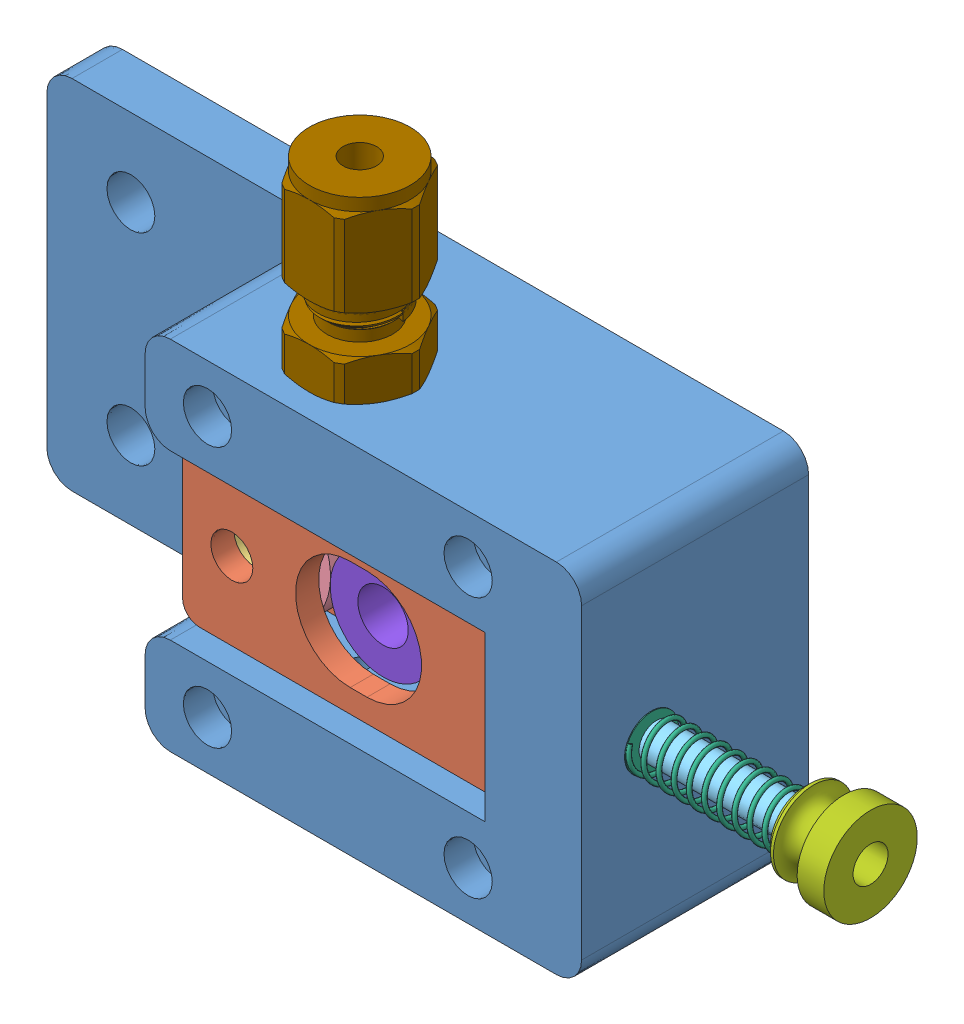
SolidWorks assembly FF-ASSY, configuration Default. Lengths in mm.
Overall size (110.17 63.8 27).
11 component instances, 10 part files, 22 mates.
Components (placement in the parent):
- P-FF-003_REV_1-1: P-FF-003_REV_1 [Default] at (4.8494 9.0702 -18.7155) size (84.61 42.5 27)
- P-FF-002_REV_1-1: P-FF-002_REV_1 [Default] at (-242.3493 -219.6941 -6.7755) size (36.5 24.5 12.5)
- washer-1: washer [Default] at (-2.4333 8.1219 2.9745) x (0.619734 -0.784812 0) z (0.784812 0.619734 0) size (8 1 8)
- washer-2: washer [Default] at (-2.4333 8.1219 -3.0255) x (-0.055167 -0.998477 0) z (0.998477 -0.055167 0) size (8 1 8)
- pusher bearing-1: pusher bearing [Default] at (-63.7572 32.1432 47.0234) x (0 0 -1) z (-0.364729 -0.931114 0) size (5 15.97 15.97)
- bolt-1: bolt [Default] at (24.2063 -23.1566 -17.7934) x (-1 0 0) z (0 0.99375 -0.111626) size (41.1 6.67 7.23)
- spring-1: spring [Default] at (41.8324 8.2291 0.0161) x (0 -0.407555 -0.913181) z (-1 0 0) size (6.79 7.12 18.5)
- knob-1: knob [Default] at (41.8278 -2.2663 4.1827) x (1 0 0) z (0 0.412808 0.910818) size (7.79 11.11 11.11)
- pusher motor-1: pusher motor [Default] at (12.7324 8.1219 -18.7155)
- pusher gear-1: pusher gear [Default] at (1.1826 -36.9282 46.7292) x (0 0 -1) z (0.968672 -0.248344 0) size (10.97 12.57 12.57)
- fitting-1: fitting [5305K261] at (6.5324 38.7719 -0.5255) x (0.866025 0 0.5) z (0 1 0) size (12 13.36 21.32)
Mates (geometry in assembly coordinates):
- Concentric1: concentric aligned: cylinder of P-FF-003_REV_1-1 through (41.7324 8.1219 -0.5255) axis (-1 0 0) radius 2.25; cylinder of P-FF-002_REV_1-1 through (28.2063 8.1219 -0.5255) axis (-1 0 0) radius 2.5
- Parallel1: parallel aligned: plane of P-FF-003_REV_1-1 through (38.7324 26.3719 8.2845) normal (0 0 1); plane of P-FF-002_REV_1-1 through (28.2063 -1.1281 5.7245) normal (0 0 1)
- Coincident1: coincident anti-aligned: plane of P-FF-002_REV_1-1 through (-8.2937 -1.1281 2.9745) normal (0 0 -1); plane of washer-1 through (-2.4333 8.1219 2.9745) normal (0 0 1)
- Concentric2: concentric aligned: cylinder of P-FF-002_REV_1-1 through (-2.4333 8.1219 2.9745) axis (0 0 1) radius 2.5; cylinder of washer-1 through (-2.4333 8.1219 1.9745) axis (0 0 1) radius 2.5
- Coincident2: coincident anti-aligned: plane of P-FF-002_REV_1-1 through (-8.2937 -1.1281 -4.0255) normal (0 0 1); plane of washer-2 through (-2.4333 8.1219 -4.0255) normal (0 0 -1)
- Concentric3: concentric anti-aligned: cylinder of P-FF-002_REV_1-1 through (-2.4333 8.1219 5.7245) axis (0 0 -1) radius 3.45; cylinder of washer-2 through (-2.4333 8.1219 -4.0255) axis (0 0 1) radius 2.5
- Coincident3: coincident anti-aligned: plane of washer-2 through (-2.4333 8.1219 -3.0255) normal (0 0 1); plane of pusher bearing-1 through (-3.0589 8.3669 -3.0255) normal (0 0 -1)
- Concentric4: concentric aligned: cylinder of washer-2 through (-2.4333 8.1219 -4.0255) axis (0 0 1) radius 2.5; cylinder of pusher bearing-1 through (-2.4333 8.1219 1.9745) axis (0 0 1) radius 2.5
- Concentric5: concentric aligned: cylinder of P-FF-003_REV_1-1 through (41.7324 8.1219 -0.5255) axis (-1 0 0) radius 2.25; cylinder of bolt-1 through (62.3063 8.1219 -0.5255) axis (-1 0 0) radius 2.0828
- Parallel2: parallel anti-aligned: plane of P-FF-002_REV_1-1 through (24.2063 10.0271 -3.8255) normal (0 0 1); plane of bolt-1 through (21.2063 6.3032 -3.6755) normal (0 0 -1)
- Coincident5: coincident anti-aligned: plane of P-FF-002_REV_1-1 through (24.2063 4.3113 -0.5255) normal (-1 0 0); plane of bolt-1 through (24.2063 9.9405 2.6245) normal (1 0 0)
- Coincident6: coincident anti-aligned: plane of P-FF-003_REV_1-1 through (41.7324 -65.6673 -12.7155) normal (1 0 0); plane of spring-1 through (41.7324 8.2291 0.0161) normal (-1 0 0)
- Tangent1: tangent: cylinder of bolt-1 through (62.3063 8.1219 -0.5255) axis (-1 0 0) radius 2.0828; face of spring-1
- Concentric6: concentric anti-aligned: cylinder of bolt-1 through (62.3063 8.1219 -0.5255) axis (-1 0 0) radius 2.0828; cylinder of knob-1 through (71.0325 8.1219 -0.5255) axis (1 0 0) radius 2.0828
- Concentric7: concentric: cylinder of P-FF-003_REV_1-1 through (12.7324 8.1219 -12.7155) axis (0 0 -1) radius 7.5; cylinder of pusher motor-1 through (12.7324 8.1219 -11.5155) axis (0 0 1) radius 2.5
- Parallel3: parallel: plane of P-FF-003_REV_1-1 through (-0.5731 -13.1281 -12.7155) normal (0 -1 0); plane of pusher motor-1 through (-5.2676 -12.8781 -19.2155) normal (0 -1 0)
- Coincident8: coincident: plane of P-FF-003_REV_1-1 through (-0.5731 -65.6673 -18.7155) normal (0 0 -1); plane of pusher motor-1 through (12.7324 8.1219 -18.7155) normal (0 0 1)
- Parallel4: parallel aligned: plane of P-FF-003_REV_1-1 through (38.7324 26.3719 8.2845) normal (0 0 1); plane of pusher gear-1 through (9.3315 -5.1432 2.9014) normal (0 0 1)
- Concentric10: concentric: cylinder of pusher motor-1 through (12.7324 8.1219 -11.5155) axis (0 0 1) radius 2.5; cylinder of pusher gear-1 through (12.7324 8.1219 2.9014) axis (0 0 1) radius 3
- Coincident10: coincident anti-aligned: plane of P-FF-003_REV_1-1 through (-0.5731 29.3719 -12.7155) normal (0 1 0); plane of fitting-1 through (13.4606 29.3719 -0.5255) normal (0 -1 0)
- Concentric11: concentric aligned: circle of P-FF-003_REV_1-1; circle of fitting-1
- Parallel5: parallel aligned: plane of P-FF-003_REV_1-1 through (38.7324 26.3719 8.2845) normal (0 0 1); plane of fitting-1 through (3.0683 34.2719 5.4745) normal (0 0 1)
